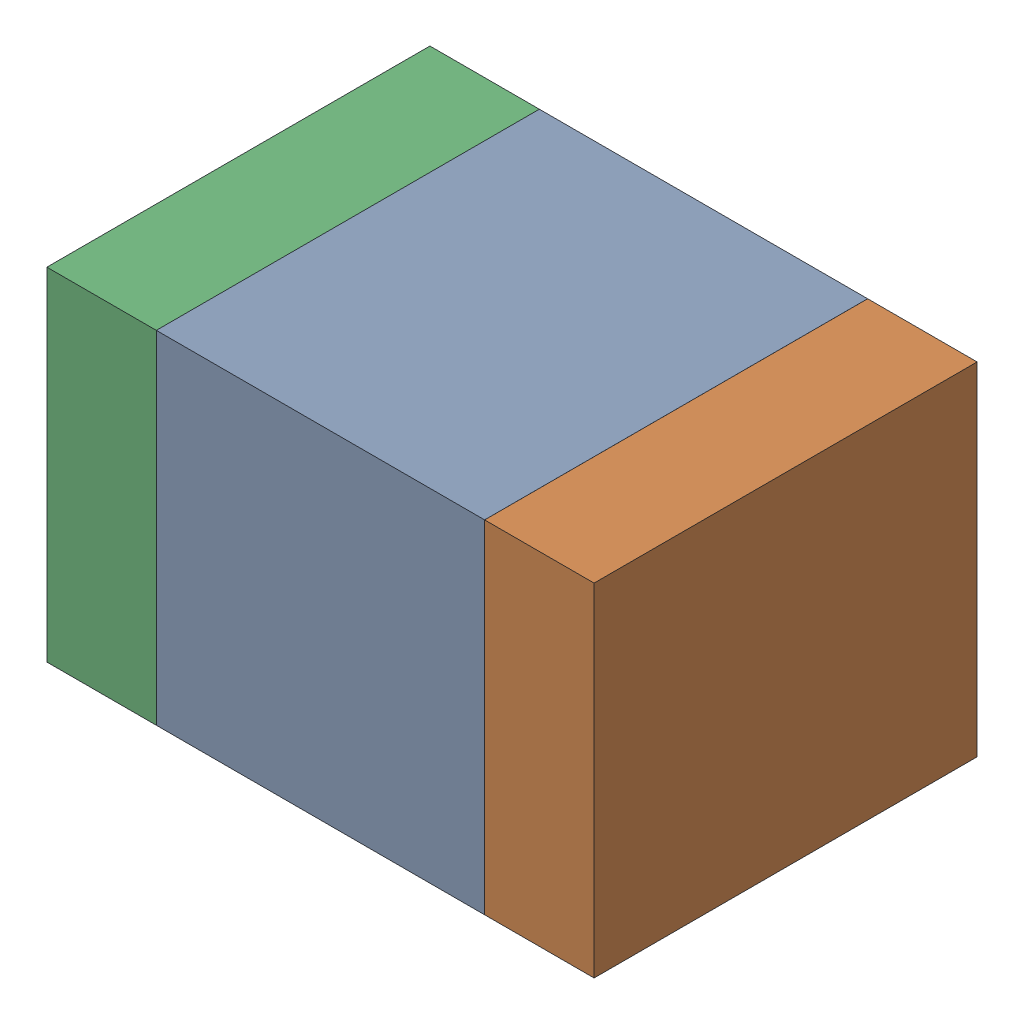
SolidWorks assembly C4, configuration ﾃﾞﾌｫﾙﾄ. Lengths in mm.
Overall size (2 1.25 1.4).
6 component instances, 2 part files, 0 mates.
Components (placement in the parent):
- 689259200-1: 689259200 [ﾃﾞﾌｫﾙﾄ] at (21.5 34.75 0) size (1.2 1.25 1.4)
  - Extruded_2-1: Extruded_2 [ﾃﾞﾌｫﾙﾄ] at origin size (1.2 1.25 1.4)
- 689248456-1: 689248456 [ﾃﾞﾌｫﾙﾄ] at (22.3001 34.75 0) size (0.4 1.25 1.4)
  - Extruded-1: Extruded [ﾃﾞﾌｫﾙﾄ] at origin size (0.4 1.25 1.4)
- 689248456-2: 689248456 [ﾃﾞﾌｫﾙﾄ] at (20.7001 34.75 0) size (0.4 1.25 1.4)
  - Extruded-1: Extruded [ﾃﾞﾌｫﾙﾄ] at origin size (0.4 1.25 1.4)
